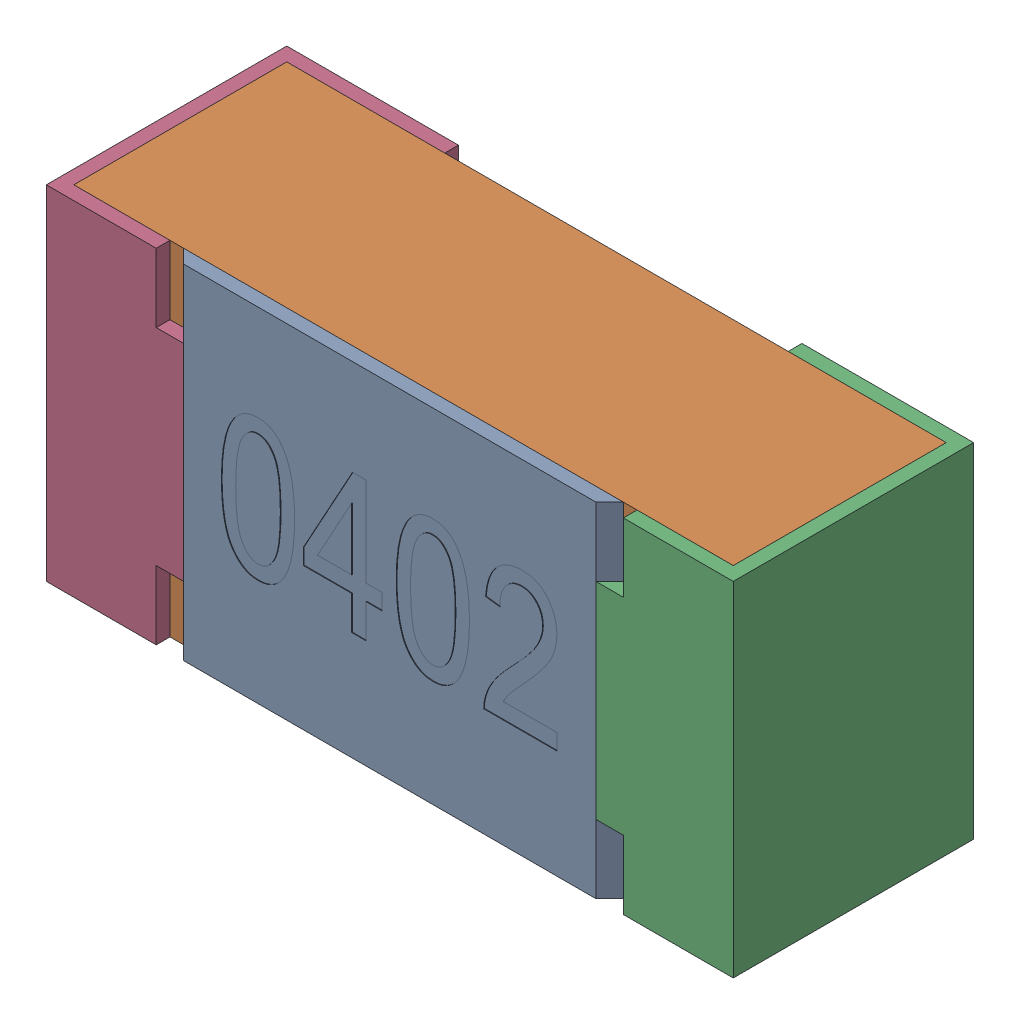
SolidWorks assembly R24, configuration Standard. Lengths in mm.
Overall size (1 0.5 0.35).
5 component instances, 4 part files, 0 mates.
Components (placement in the parent):
- R24-subassembly-1-1: R24-subassembly-1 [Standard] at (-11.4999 -3.8 0) x (1 0 0) z (0 0 1) size (1 0.5 0.35)
  - User Library-R_0402-1: User Library-R_0402 [Standard] at origin size (0.64 0.5 0.02)
  - User Library-R_0402-1-1: User Library-R_0402-1 [Standard] at origin size (0.96 0.5 0.31)
  - User Library-R_0402-2-1: User Library-R_0402-2 [Standard] at origin size (0.25 0.5 0.35)
  - User Library-R_0402-3-1: User Library-R_0402-3 [Standard] at origin size (0.25 0.5 0.35)
